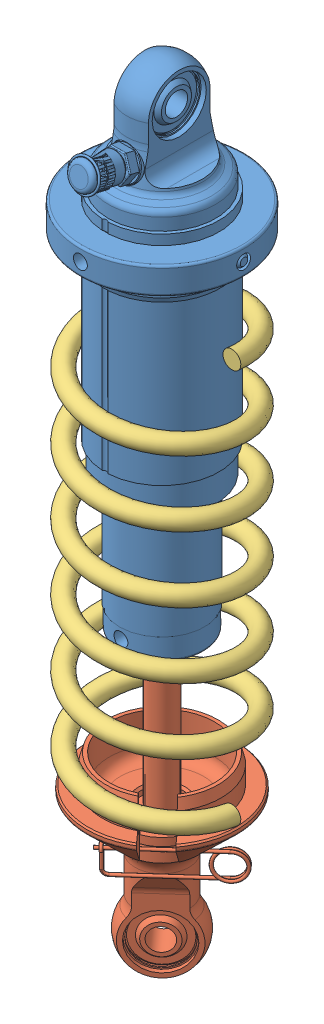
SolidWorks assembly Damper, configuration Default. Lengths in mm.
Overall size (90.27 297.02 92.18).
3 component instances, 3 part files, 3 mates.
Components (placement in the parent):
- Quarter Midget Damper Base-1: Quarter Midget Damper Base [Default] at (48.9022 65.394 98.7123) size (58.08 180.03 83.54)
- Quarter Midget Damper Rod-1: Quarter Midget Damper Rod [Default] at (48.9022 80.0512 98.7123) x (0.666673 0 0.74535) z (-0.74535 0 0.666673) size (53.04 297.02 73.68)
- Spring-1: Spring [Default] at (48.9022 12.665 98.7123) x (1 0 0) z (0 1 0) size (62.23 62.23 146.05)
Mates (geometry in assembly coordinates):
- Concentric1: concentric aligned: circle of Quarter Midget Damper Base-1; circle of Quarter Midget Damper Rod-1
- Concentric2: concentric anti-aligned: cylinder of Quarter Midget Damper Base-1 through (48.9022 99.7094 98.7123) axis (0 -1 0) radius 15.0749; circle of Spring-1
- Tangent1: tangent: plane of Quarter Midget Damper Rod-1 through (10.4877 9.49 96.5803) normal (0 1 0); circle of Spring-1
